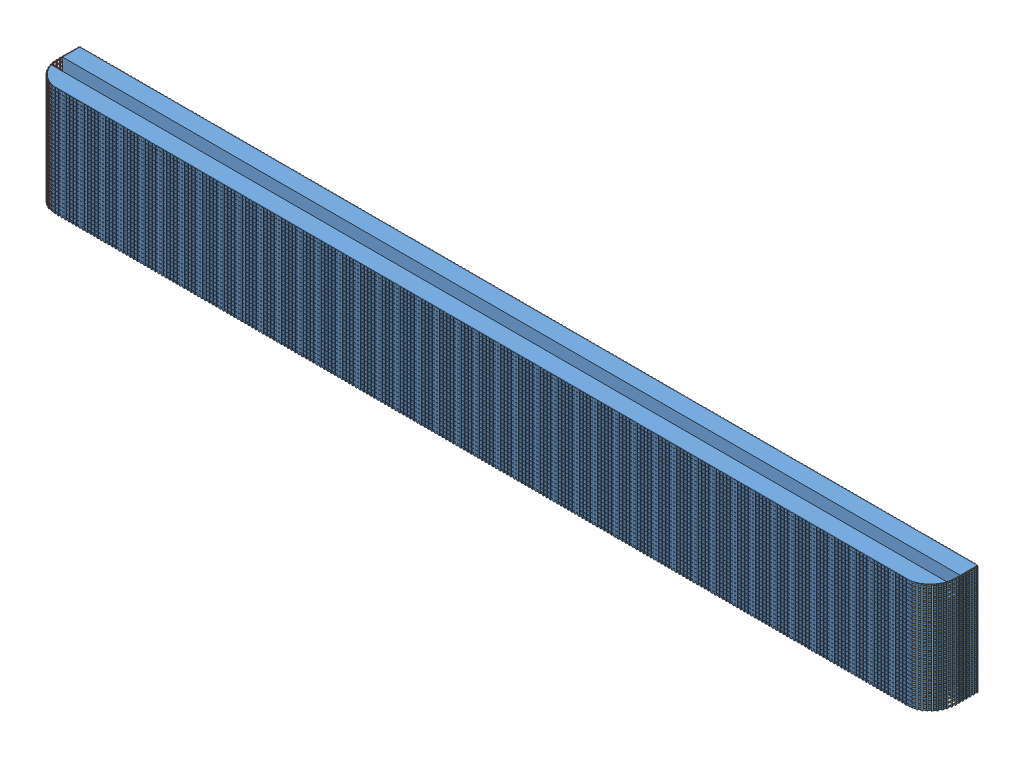
SolidWorks assembly B_neo_texture_55mm, configuration Default. Lengths in mm.
Overall size (450.8 54.89 24).
93 component instances, 5 part files, 16 mates.
Components (placement in the parent):
- B_neo_texture_55mm-1: B_neo_texture_55mm [Default] at origin size (450 54.89 24)
- Part3^B_neo_texture_55mm-1: Part3^B_neo_texture_55mm [Default] at (0 54.89 0) x (1 0 0) z (0 1 0) size (9.65 23.39 0.6) (virtual)
- Part4^B_neo_texture_55mm-1: Part4^B_neo_texture_55mm [Default] at (0 54.89 0) x (1 0 0) z (0 1 0) size (9.65 23.39 0.6) (virtual)
- Part5^B_neo_texture_55mm-1: Part5^B_neo_texture_55mm [Default] at (0 54.89 0) x (1 0 0) z (0 1 0) size (0.2 0.6 54.89) (virtual)
- Part6^B_neo_texture_55mm-1: Part6^B_neo_texture_55mm [Default] at (0 54.89 0) x (1 0 0) z (0 1 0) size (0.2 0.6 54.89) (virtual)
- Part6^B_neo_texture_55mm-2: Part6^B_neo_texture_55mm [Default] at (0 54.89 1.8005) x (1 0 0) z (0 1 0) size (0.2 0.6 54.89) (virtual)
- Part6^B_neo_texture_55mm-3: Part6^B_neo_texture_55mm [Default] at (0 54.89 3.601) x (1 0 0) z (0 1 0) size (0.2 0.6 54.89) (virtual)
- Part6^B_neo_texture_55mm-4: Part6^B_neo_texture_55mm [Default] at (0 54.89 5.3999) x (1 0 0) z (0 1 0) size (0.2 0.6 54.89) (virtual)
- Part6^B_neo_texture_55mm-5: Part6^B_neo_texture_55mm [Default] at (0 54.89 7.2004) x (1 0 0) z (0 1 0) size (0.2 0.6 54.89) (virtual)
- Part6^B_neo_texture_55mm-6: Part6^B_neo_texture_55mm [Default] at (0 54.89 9.0008) x (1 0 0) z (0 1 0) size (0.2 0.6 54.89) (virtual)
- Part6^B_neo_texture_55mm-7: Part6^B_neo_texture_55mm [Default] at (-0.1676 54.89 7.2359) x (0.999969 0 0.007918) z (0 1 0) size (0.2 0.6 54.89) (virtual)
- Part6^B_neo_texture_55mm-8: Part6^B_neo_texture_55mm [Default] at (1.5205 54.89 -55.2373) x (0.988662 0 0.150155) z (0 1 0) size (0.2 0.6 54.89) (virtual)
- Part6^B_neo_texture_55mm-9: Part6^B_neo_texture_55mm [Default] at (12.0944 54.89 -116.8818) x (0.957196 0 0.289441) z (0 1 0) size (0.2 0.6 54.89) (virtual)
- Part6^B_neo_texture_55mm-10: Part6^B_neo_texture_55mm [Default] at (31.3222 54.89 -176.3462) x (0.906258 0 0.422724) z (0 1 0) size (0.2 0.6 54.89) (virtual)
- Part6^B_neo_texture_55mm-11: Part6^B_neo_texture_55mm [Default] at (58.8401 54.89 -232.5078) x (0.836814 0 0.547487) z (0 1 0) size (0.2 0.6 54.89) (virtual)
- Part6^B_neo_texture_55mm-12: Part6^B_neo_texture_55mm [Default] at (94.0476 54.89 -284.1417) x (0.750378 0 0.661009) z (0 1 0) size (0.2 0.6 54.89) (virtual)
- Part6^B_neo_texture_55mm-13: Part6^B_neo_texture_55mm [Default] at (136.3055 54.89 -330.2964) x (0.648521 0 0.761197) z (0 1 0) size (0.2 0.6 54.89) (virtual)
- Part6^B_neo_texture_55mm-14: Part6^B_neo_texture_55mm [Default] at (184.649 54.89 -369.9151) x (0.533569 0 0.845756) z (0 1 0) size (0.2 0.6 54.89) (virtual)
- Part6^B_neo_texture_55mm-15: Part6^B_neo_texture_55mm [Default] at (238.1403 54.89 -402.2497) x (0.40775 0 0.913094) z (0 1 0) size (0.2 0.6 54.89) (virtual)
- Part5^B_neo_texture_55mm-2: Part5^B_neo_texture_55mm [Default] at (0 54.89 1.7991) x (1 0 0) z (0 1 0) size (0.2 0.6 54.89) (virtual)
- Part5^B_neo_texture_55mm-3: Part5^B_neo_texture_55mm [Default] at (0 54.89 3.5999) x (1 0 0) z (0 1 0) size (0.2 0.6 54.89) (virtual)
- Part5^B_neo_texture_55mm-4: Part5^B_neo_texture_55mm [Default] at (0 54.89 5.4006) x (1 0 0) z (0 1 0) size (0.2 0.6 54.89) (virtual)
- Part5^B_neo_texture_55mm-5: Part5^B_neo_texture_55mm [Default] at (0 54.89 7.1997) x (1 0 0) z (0 1 0) size (0.2 0.6 54.89) (virtual)
- Part5^B_neo_texture_55mm-6: Part5^B_neo_texture_55mm [Default] at (0 54.89 9.0005) x (1 0 0) z (0 1 0) size (0.2 0.6 54.89) (virtual)
- Part5^B_neo_texture_55mm-7: Part5^B_neo_texture_55mm [Default] at (0.1817 54.89 10.7992) x (0.999969 0 -0.007918) z (0 1 0) size (0.2 0.6 54.89) (virtual)
- Part5^B_neo_texture_55mm-8: Part5^B_neo_texture_55mm [Default] at (3.5831 54.89 12.3329) x (0.988652 0 -0.150222) z (0 1 0) size (0.2 0.6 54.89) (virtual)
- Part5^B_neo_texture_55mm-9: Part5^B_neo_texture_55mm [Default] at (7.1689 54.89 13.367) x (0.95718 0 -0.289493) z (0 1 0) size (0.2 0.6 54.89) (virtual)
- Part5^B_neo_texture_55mm-10: Part5^B_neo_texture_55mm [Default] at (10.8644 54.89 13.8798) x (0.906212 0 -0.422823) z (0 1 0) size (0.2 0.6 54.89) (virtual)
- Part5^B_neo_texture_55mm-11: Part5^B_neo_texture_55mm [Default] at (14.5929 54.89 13.8614) x (0.836829 0 -0.547465) z (0 1 0) size (0.2 0.6 54.89) (virtual)
- Part5^B_neo_texture_55mm-12: Part5^B_neo_texture_55mm [Default] at (18.2837 54.89 13.3121) x (0.750343 0 -0.661049) z (0 1 0) size (0.2 0.6 54.89) (virtual)
- Part5^B_neo_texture_55mm-13: Part5^B_neo_texture_55mm [Default] at (21.8567 54.89 12.2435) x (0.648626 0 -0.761108) z (0 1 0) size (0.2 0.6 54.89) (virtual)
- Part5^B_neo_texture_55mm-14: Part5^B_neo_texture_55mm [Default] at (25.244 54.89 10.6757) x (0.533601 0 -0.845736) z (0 1 0) size (0.2 0.6 54.89) (virtual)
- Part5^B_neo_texture_55mm-15: Part5^B_neo_texture_55mm [Default] at (28.3725 54.89 8.6422) x (0.407737 0 -0.913099) z (0 1 0) size (0.2 0.6 54.89) (virtual)
- Part3^B_neo_texture_55mm-2: Part3^B_neo_texture_55mm [Default] at (0 53.09 0) x (1 0 0) z (0 1 0) size (9.65 23.39 0.6) (virtual)
- Part3^B_neo_texture_55mm-3: Part3^B_neo_texture_55mm [Default] at (0 51.29 0) x (1 0 0) z (0 1 0) size (9.65 23.39 0.6) (virtual)
- Part3^B_neo_texture_55mm-4: Part3^B_neo_texture_55mm [Default] at (0 49.49 0) x (1 0 0) z (0 1 0) size (9.65 23.39 0.6) (virtual)
- Part3^B_neo_texture_55mm-5: Part3^B_neo_texture_55mm [Default] at (0 47.69 0) x (1 0 0) z (0 1 0) size (9.65 23.39 0.6) (virtual)
- Part3^B_neo_texture_55mm-6: Part3^B_neo_texture_55mm [Default] at (0 45.89 0) x (1 0 0) z (0 1 0) size (9.65 23.39 0.6) (virtual)
- Part3^B_neo_texture_55mm-7: Part3^B_neo_texture_55mm [Default] at (0 44.09 0) x (1 0 0) z (0 1 0) size (9.65 23.39 0.6) (virtual)
- Part3^B_neo_texture_55mm-8: Part3^B_neo_texture_55mm [Default] at (0 42.29 0) x (1 0 0) z (0 1 0) size (9.65 23.39 0.6) (virtual)
- Part3^B_neo_texture_55mm-9: Part3^B_neo_texture_55mm [Default] at (0 40.49 0) x (1 0 0) z (0 1 0) size (9.65 23.39 0.6) (virtual)
- Part3^B_neo_texture_55mm-10: Part3^B_neo_texture_55mm [Default] at (0 38.69 0) x (1 0 0) z (0 1 0) size (9.65 23.39 0.6) (virtual)
- Part3^B_neo_texture_55mm-11: Part3^B_neo_texture_55mm [Default] at (0 36.89 0) x (1 0 0) z (0 1 0) size (9.65 23.39 0.6) (virtual)
- Part3^B_neo_texture_55mm-12: Part3^B_neo_texture_55mm [Default] at (0 35.09 0) x (1 0 0) z (0 1 0) size (9.65 23.39 0.6) (virtual)
- Part3^B_neo_texture_55mm-13: Part3^B_neo_texture_55mm [Default] at (0 33.29 0) x (1 0 0) z (0 1 0) size (9.65 23.39 0.6) (virtual)
- Part3^B_neo_texture_55mm-14: Part3^B_neo_texture_55mm [Default] at (0 31.49 0) x (1 0 0) z (0 1 0) size (9.65 23.39 0.6) (virtual)
- Part3^B_neo_texture_55mm-15: Part3^B_neo_texture_55mm [Default] at (0 29.69 0) x (1 0 0) z (0 1 0) size (9.65 23.39 0.6) (virtual)
- Part3^B_neo_texture_55mm-16: Part3^B_neo_texture_55mm [Default] at (0 27.89 0) x (1 0 0) z (0 1 0) size (9.65 23.39 0.6) (virtual)
- Part3^B_neo_texture_55mm-17: Part3^B_neo_texture_55mm [Default] at (0 26.09 0) x (1 0 0) z (0 1 0) size (9.65 23.39 0.6) (virtual)
- Part3^B_neo_texture_55mm-18: Part3^B_neo_texture_55mm [Default] at (0 24.29 0) x (1 0 0) z (0 1 0) size (9.65 23.39 0.6) (virtual)
- Part3^B_neo_texture_55mm-19: Part3^B_neo_texture_55mm [Default] at (0 22.49 0) x (1 0 0) z (0 1 0) size (9.65 23.39 0.6) (virtual)
- Part3^B_neo_texture_55mm-20: Part3^B_neo_texture_55mm [Default] at (0 20.69 0) x (1 0 0) z (0 1 0) size (9.65 23.39 0.6) (virtual)
- Part3^B_neo_texture_55mm-21: Part3^B_neo_texture_55mm [Default] at (0 18.89 0) x (1 0 0) z (0 1 0) size (9.65 23.39 0.6) (virtual)
- Part3^B_neo_texture_55mm-22: Part3^B_neo_texture_55mm [Default] at (0 17.09 0) x (1 0 0) z (0 1 0) size (9.65 23.39 0.6) (virtual)
- Part3^B_neo_texture_55mm-23: Part3^B_neo_texture_55mm [Default] at (0 15.29 0) x (1 0 0) z (0 1 0) size (9.65 23.39 0.6) (virtual)
- Part3^B_neo_texture_55mm-24: Part3^B_neo_texture_55mm [Default] at (0 13.49 0) x (1 0 0) z (0 1 0) size (9.65 23.39 0.6) (virtual)
- Part3^B_neo_texture_55mm-25: Part3^B_neo_texture_55mm [Default] at (0 11.69 0) x (1 0 0) z (0 1 0) size (9.65 23.39 0.6) (virtual)
- Part3^B_neo_texture_55mm-26: Part3^B_neo_texture_55mm [Default] at (0 9.89 0) x (1 0 0) z (0 1 0) size (9.65 23.39 0.6) (virtual)
- Part3^B_neo_texture_55mm-27: Part3^B_neo_texture_55mm [Default] at (0 8.09 0) x (1 0 0) z (0 1 0) size (9.65 23.39 0.6) (virtual)
- Part3^B_neo_texture_55mm-28: Part3^B_neo_texture_55mm [Default] at (0 6.29 0) x (1 0 0) z (0 1 0) size (9.65 23.39 0.6) (virtual)
- Part3^B_neo_texture_55mm-29: Part3^B_neo_texture_55mm [Default] at (0 4.49 0) x (1 0 0) z (0 1 0) size (9.65 23.39 0.6) (virtual)
- Part3^B_neo_texture_55mm-30: Part3^B_neo_texture_55mm [Default] at (0 2.69 0) x (1 0 0) z (0 1 0) size (9.65 23.39 0.6) (virtual)
- Part3^B_neo_texture_55mm-31: Part3^B_neo_texture_55mm [Default] at (0 0.89 0) x (1 0 0) z (0 1 0) size (9.65 23.39 0.6) (virtual)
- Part4^B_neo_texture_55mm-2: Part4^B_neo_texture_55mm [Default] at (0 53.09 0) x (1 0 0) z (0 1 0) size (9.65 23.39 0.6) (virtual)
- Part4^B_neo_texture_55mm-3: Part4^B_neo_texture_55mm [Default] at (0 51.29 0) x (1 0 0) z (0 1 0) size (9.65 23.39 0.6) (virtual)
- Part4^B_neo_texture_55mm-4: Part4^B_neo_texture_55mm [Default] at (0 49.49 0) x (1 0 0) z (0 1 0) size (9.65 23.39 0.6) (virtual)
- Part4^B_neo_texture_55mm-5: Part4^B_neo_texture_55mm [Default] at (0 47.69 0) x (1 0 0) z (0 1 0) size (9.65 23.39 0.6) (virtual)
- Part4^B_neo_texture_55mm-6: Part4^B_neo_texture_55mm [Default] at (0 45.89 0) x (1 0 0) z (0 1 0) size (9.65 23.39 0.6) (virtual)
- Part4^B_neo_texture_55mm-7: Part4^B_neo_texture_55mm [Default] at (0 44.09 0) x (1 0 0) z (0 1 0) size (9.65 23.39 0.6) (virtual)
- Part4^B_neo_texture_55mm-8: Part4^B_neo_texture_55mm [Default] at (0 42.29 0) x (1 0 0) z (0 1 0) size (9.65 23.39 0.6) (virtual)
- Part4^B_neo_texture_55mm-9: Part4^B_neo_texture_55mm [Default] at (0 40.49 0) x (1 0 0) z (0 1 0) size (9.65 23.39 0.6) (virtual)
- Part4^B_neo_texture_55mm-10: Part4^B_neo_texture_55mm [Default] at (0 38.69 0) x (1 0 0) z (0 1 0) size (9.65 23.39 0.6) (virtual)
- Part4^B_neo_texture_55mm-11: Part4^B_neo_texture_55mm [Default] at (0 36.89 0) x (1 0 0) z (0 1 0) size (9.65 23.39 0.6) (virtual)
- Part4^B_neo_texture_55mm-12: Part4^B_neo_texture_55mm [Default] at (0 35.09 0) x (1 0 0) z (0 1 0) size (9.65 23.39 0.6) (virtual)
- Part4^B_neo_texture_55mm-13: Part4^B_neo_texture_55mm [Default] at (0 33.29 0) x (1 0 0) z (0 1 0) size (9.65 23.39 0.6) (virtual)
- Part4^B_neo_texture_55mm-14: Part4^B_neo_texture_55mm [Default] at (0 31.49 0) x (1 0 0) z (0 1 0) size (9.65 23.39 0.6) (virtual)
- Part4^B_neo_texture_55mm-15: Part4^B_neo_texture_55mm [Default] at (0 29.69 0) x (1 0 0) z (0 1 0) size (9.65 23.39 0.6) (virtual)
- Part4^B_neo_texture_55mm-16: Part4^B_neo_texture_55mm [Default] at (0 27.89 0) x (1 0 0) z (0 1 0) size (9.65 23.39 0.6) (virtual)
- Part4^B_neo_texture_55mm-17: Part4^B_neo_texture_55mm [Default] at (0 26.09 0) x (1 0 0) z (0 1 0) size (9.65 23.39 0.6) (virtual)
- Part4^B_neo_texture_55mm-18: Part4^B_neo_texture_55mm [Default] at (0 24.29 0) x (1 0 0) z (0 1 0) size (9.65 23.39 0.6) (virtual)
- Part4^B_neo_texture_55mm-19: Part4^B_neo_texture_55mm [Default] at (0 22.49 0) x (1 0 0) z (0 1 0) size (9.65 23.39 0.6) (virtual)
- Part4^B_neo_texture_55mm-20: Part4^B_neo_texture_55mm [Default] at (0 20.69 0) x (1 0 0) z (0 1 0) size (9.65 23.39 0.6) (virtual)
- Part4^B_neo_texture_55mm-21: Part4^B_neo_texture_55mm [Default] at (0 18.89 0) x (1 0 0) z (0 1 0) size (9.65 23.39 0.6) (virtual)
- Part4^B_neo_texture_55mm-22: Part4^B_neo_texture_55mm [Default] at (0 17.09 0) x (1 0 0) z (0 1 0) size (9.65 23.39 0.6) (virtual)
- Part4^B_neo_texture_55mm-23: Part4^B_neo_texture_55mm [Default] at (0 15.29 0) x (1 0 0) z (0 1 0) size (9.65 23.39 0.6) (virtual)
- Part4^B_neo_texture_55mm-24: Part4^B_neo_texture_55mm [Default] at (0 13.49 0) x (1 0 0) z (0 1 0) size (9.65 23.39 0.6) (virtual)
- Part4^B_neo_texture_55mm-25: Part4^B_neo_texture_55mm [Default] at (0 11.69 0) x (1 0 0) z (0 1 0) size (9.65 23.39 0.6) (virtual)
- Part4^B_neo_texture_55mm-26: Part4^B_neo_texture_55mm [Default] at (0 9.89 0) x (1 0 0) z (0 1 0) size (9.65 23.39 0.6) (virtual)
- Part4^B_neo_texture_55mm-27: Part4^B_neo_texture_55mm [Default] at (0 8.09 0) x (1 0 0) z (0 1 0) size (9.65 23.39 0.6) (virtual)
- Part4^B_neo_texture_55mm-28: Part4^B_neo_texture_55mm [Default] at (0 6.29 0) x (1 0 0) z (0 1 0) size (9.65 23.39 0.6) (virtual)
- Part4^B_neo_texture_55mm-29: Part4^B_neo_texture_55mm [Default] at (0 4.49 0) x (1 0 0) z (0 1 0) size (9.65 23.39 0.6) (virtual)
- Part4^B_neo_texture_55mm-30: Part4^B_neo_texture_55mm [Default] at (0 2.69 0) x (1 0 0) z (0 1 0) size (9.65 23.39 0.6) (virtual)
- Part4^B_neo_texture_55mm-31: Part4^B_neo_texture_55mm [Default] at (0 0.89 0) x (1 0 0) z (0 1 0) size (9.65 23.39 0.6) (virtual)
Mates (geometry in assembly coordinates):
- InPlace1: in place: plane of B_neo_texture_55mm-1 through (450 54.89 -14.7) normal (0 1 0); plane of ? through (0 54.89 0) normal (0 1 0); moOrthogonalPlaneRef_w of B_neo_texture_55mm-1 through (450 54.89 -14.7) normal (0 1 0); plane of ? through (0 54.89 0) normal (0 0 -1); plane of B_neo_texture_55mm-1 through (450 54.89 -14.7) normal (0 1 0); plane of ? through (0 54.89 0) normal (1 0 0); plane of B_neo_texture_55mm-1 through (450 54.89 -14.7) normal (0 1 0); unknown of ?
- Coincident1: coincident aligned: plane of ?; plane of ?
- Coincident2: coincident aligned: moOrthogonalPlaneRef_w of B_neo_texture_55mm-1 through (0 54.89 0) normal (0 0 -1); plane of Part3^Assem1-1 through (0 54.89 0) normal (0 0 -1)
- Coincident3: coincident anti-aligned: moOrthogonalPlaneRef_w of B_neo_texture_55mm-1 through (0 54.89 0) normal (-1 0 0); plane of Part3^Assem1-1 through (0 54.89 0) normal (1 0 0)
- InPlace2: in place: plane of B_neo_texture_55mm-1 through (450 54.89 -14.7) normal (0 1 0); plane of ? through (0 54.89 0) normal (0 1 0); plane of B_neo_texture_55mm-1 through (450 54.89 -14.7) normal (0 1 0); plane of ? through (0 54.89 0) normal (0 0 -1); plane of B_neo_texture_55mm-1 through (450 54.89 -14.7) normal (0 1 0); plane of ? through (0 54.89 0) normal (1 0 0); plane of B_neo_texture_55mm-1 through (450 54.89 -14.7) normal (0 1 0); unknown of ?
- Coincident4: coincident aligned: plane of ?; plane of ?
- Coincident5: coincident aligned: moOrthogonalPlaneRef_w of B_neo_texture_55mm-1 through (0 54.89 0) normal (0 0 -1); plane of Part4^Assem1-1 through (0 54.89 0) normal (0 0 -1)
- Coincident6: coincident anti-aligned: moOrthogonalPlaneRef_w of B_neo_texture_55mm-1 through (0 54.89 0) normal (-1 0 0); plane of Part4^Assem1-1 through (0 54.89 0) normal (1 0 0)
- InPlace3: in place: plane of ? through (12.6 54.89 -12.2) normal (0 1 0); plane of ? through (0 54.89 0) normal (0 1 0); plane of ? through (12.6 54.89 -12.2) normal (0 1 0); plane of ? through (0 54.89 0) normal (0 0 -1); plane of ? through (12.6 54.89 -12.2) normal (0 1 0); plane of ? through (0 54.89 0) normal (1 0 0); plane of ? through (12.6 54.89 -12.2) normal (0 1 0); unknown of ?
- Coincident7: coincident aligned: plane of ?; plane of ?
- Coincident8: coincident aligned: moOrthogonalPlaneRef_w of Part3^Assem1-1 through (0 54.89 0) normal (0 0 -1); plane of Part5^Assem1-1 through (0 54.89 0) normal (0 0 -1)
- Coincident9: coincident anti-aligned: moOrthogonalPlaneRef_w of Part3^Assem1-1 through (0 54.89 0) normal (-1 0 0); plane of Part5^Assem1-1 through (0 54.89 0) normal (1 0 0)
- InPlace4: in place: plane of ? through (437.4 54.89 -12.2) normal (0 1 0); plane of ? through (0 54.89 0) normal (0 1 0); plane of ? through (437.4 54.89 -12.2) normal (0 1 0); plane of ? through (0 54.89 0) normal (0 0 -1); plane of ? through (437.4 54.89 -12.2) normal (0 1 0); plane of ? through (0 54.89 0) normal (1 0 0); plane of ? through (437.4 54.89 -12.2) normal (0 1 0); unknown of ?
- Coincident10: coincident aligned: plane of ?; plane of ?
- Coincident11: coincident aligned: moOrthogonalPlaneRef_w of Part4^Assem1-1 through (0 54.89 0) normal (0 0 -1); plane of Part6^Assem1-1 through (0 54.89 0) normal (0 0 -1)
- Coincident12: coincident anti-aligned: moOrthogonalPlaneRef_w of Part4^Assem1-1 through (0 54.89 0) normal (-1 0 0); plane of Part6^Assem1-1 through (0 54.89 0) normal (1 0 0)
